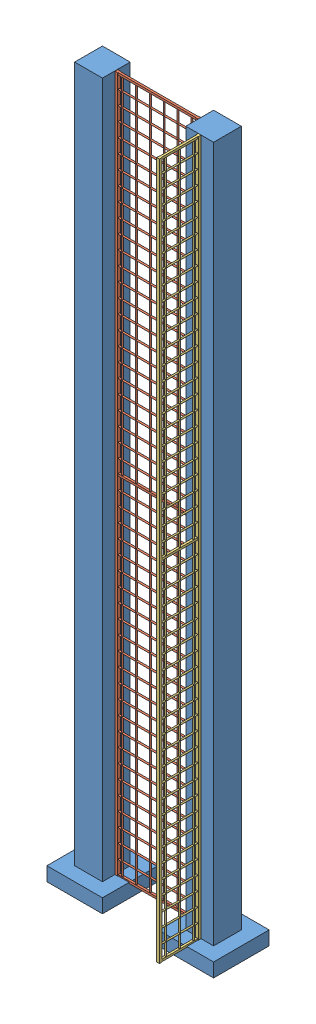
SolidWorks assembly bariera_angolo, configuration Default. Lengths in mm.
Overall size (600 2555 300).
4 component instances, 3 part files, 19 mates.
Components (placement in the parent):
- palo_barriera-1: palo_barriera [Default] at origin size (200 2555 200)
- palo_barriera-4: palo_barriera [Default] at (-400 0 0) size (200 2555 200)
- rete 300-1: rete 300 [Default] at (-77.5 2550.25 0) x (-1 0 0) z (0 -1 0) size (300 10 2507.5)
- rete200-2: rete200 [Default] at (0 51.25 172.5) x (0 0 -1) z (0 1 0) size (150 10 2507.5)
Mates (geometry in assembly coordinates):
- Coincidente1: coordinate: point of palo_barriera-1
- Distanza1: distance = 1750 mm aligned: plane of palo_barriera-1 through (0 0 0) normal (0 0 1); plane of palo_barriera-2 through (0 0 1750) normal (0 0 1)
- Coincidente3: coincident aligned: plane of palo_barriera-1 through (-50 2550 -50) normal (-1 0 0); plane of palo_barriera-2 through (-50 2550 1700) normal (-1 0 0)
- Coincidente4: coincident aligned: plane of palo_barriera-1 through (0 2555 0) normal (0 1 0); plane of palo_barriera-2 through (0 2555 1750) normal (0 1 0)
- Coincidente5: coincident aligned: plane of palo_barriera-1 through (50 2550 -50) normal (1 0 0); plane of palo_barriera-3 through (50 2550 250) normal (1 0 0)
- Coincidente6: coincident aligned: plane of palo_barriera-1 through (0 2555 0) normal (0 1 0); plane of palo_barriera-3 through (0 2555 300) normal (0 1 0)
- Distanza2: distance = 300 mm aligned: plane of palo_barriera-1 through (0 0 0) normal (0 0 1); plane of palo_barriera-3 through (0 0 300) normal (0 0 1)
- Coincidente8: coincident aligned: plane of palo_barriera-1 through (0 2555 0) normal (0 1 0); plane of palo_barriera-4 through (-400 2555 0) normal (0 1 0)
- Coincidente9: coincident aligned: plane of palo_barriera-1 through (-50 2550 -50) normal (0 0 -1); plane of palo_barriera-4 through (-450 2550 -50) normal (0 0 -1)
- Distanza4: distance = 400 mm aligned: plane of palo_barriera-4 through (-400 0 0) normal (1 0 0); plane of palo_barriera-1 through (0 0 0) normal (1 0 0)
- Distanza11: distance = 1 mm aligned: plane of palo_barriera-1 through (0 2555 0) normal (0 1 0); plane of rete 300-1 through (-1010.6066 2554 -3.75) normal (0 1 0)
- Distanza5: distance = 45 mm aligned: plane of rete 300-1 through (-340 2568.1421 -5) normal (0 0 -1); plane of palo_barriera-4 through (-450 2550 -50) normal (0 0 -1)
- Coincidente20: coincident anti-aligned: plane of palo_barriera-4 through (-350 2550 -50) normal (1 0 0); plane of rete 300-1 through (-350 3231.2262 -24.5677) normal (-1 0 0)
- Coincidente18: coincident anti-aligned: plane of palo_barriera-3 through (-50 2550 350) normal (0 0 1); plane of rete2m-1 through (-171.1689 41.25 350) normal (0 0 -1)
- Coincidente19: coincident aligned: plane of palo_barriera-3 through (0 2555 300) normal (0 1 0); plane of rete2m-1 through (-3.75 2555 -710.6066) normal (0 1 0)
- Distanza9: distance = 45 mm aligned: plane of rete2m-1 through (5 2569.1421 1700) normal (1 0 0); plane of palo_barriera-3 through (50 2550 250) normal (1 0 0)
- Coincidente21: coincident aligned: plane of palo_barriera-1 through (0 2555 0) normal (0 1 0); plane of rete200-2 through (-3.75 2555 -760.6066) normal (0 1 0)
- Coincidente22: coincident anti-aligned: plane of palo_barriera-1 through (-50 2550 50) normal (0 0 1); plane of rete200-2 through (-24.5677 -883.5079 50) normal (0 0 -1)
- Distanza12: distance = 45 mm aligned: plane of rete200-2 through (5 2569.1421 200) normal (1 0 0); plane of palo_barriera-1 through (50 2550 -50) normal (1 0 0)
